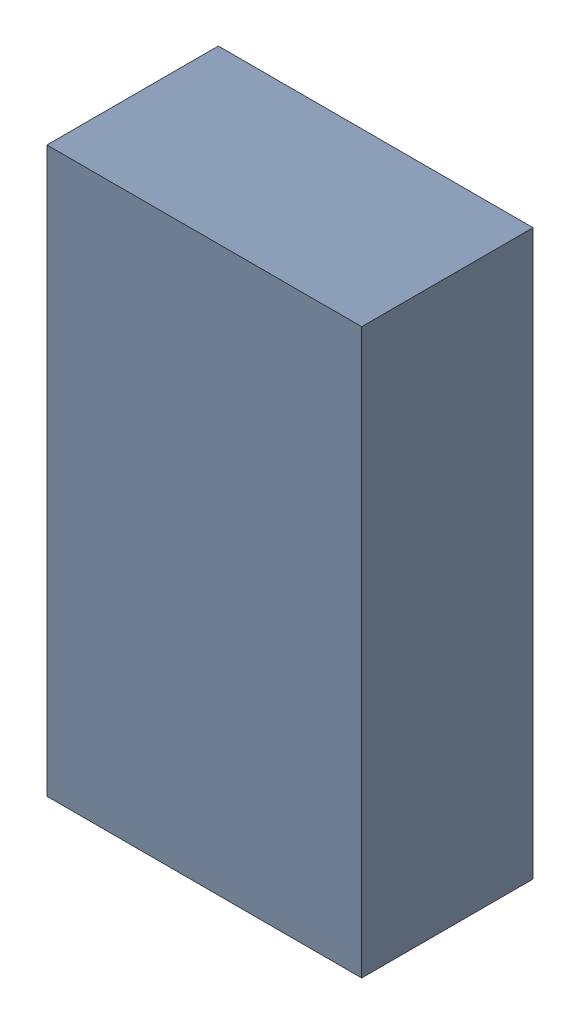
SolidWorks assembly R23, configuration Default. Lengths in mm.
Overall size (1.01 1.81 0.56).
3 component instances, 2 part files, 0 mates.
Components (placement in the parent):
- 1088887696-1: 1088887696 [Default] at (4.075 19.25 -2.194) size (1.01 1.81 0.55)
  - Extruded-29-1: Extruded-29 [Default] at origin size (1.01 1.81 0.55)
- R0603-1: R0603 [Default] at (4.0749 19.2499 -1.644) x (0 -1 0) z (1 0 0) size (1.7 0.56 0.8)
